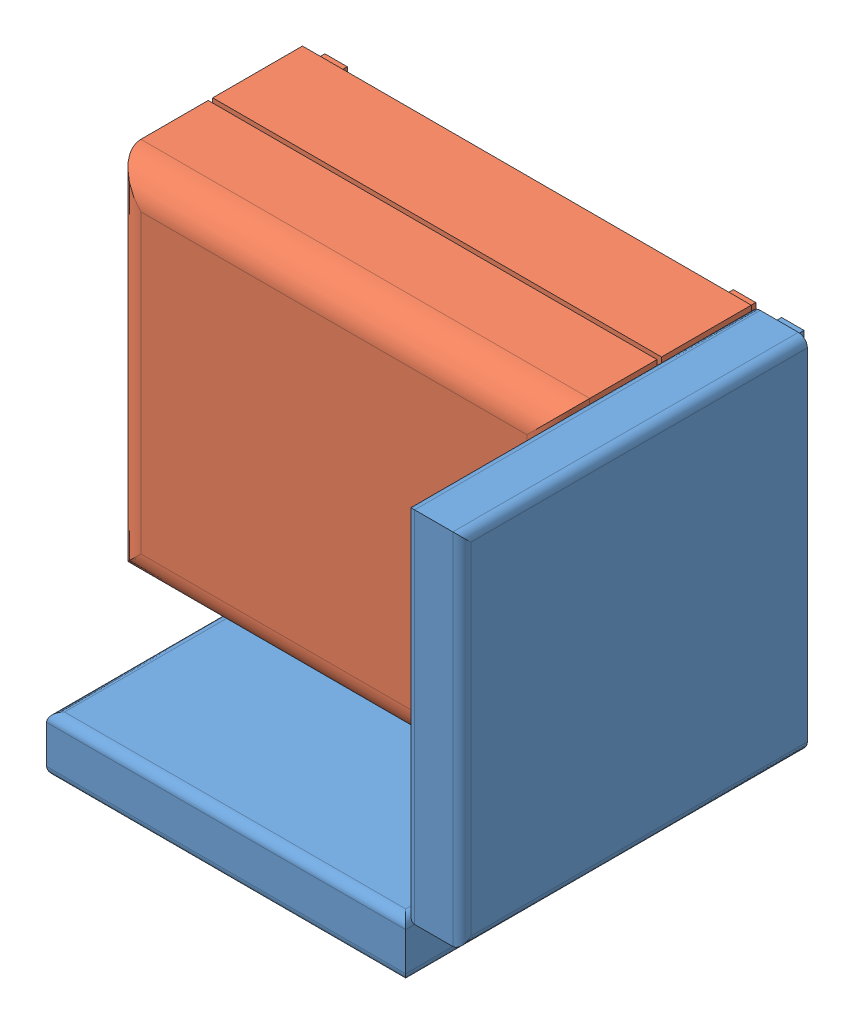
SolidWorks assembly Sofa-L, configuration Standard. Lengths in mm.
Overall size (1125 925 800).
3 component instances, 2 part files, 6 mates.
Components (placement in the parent):
- Rückenstütze-80x80-1: Rückenstütze-80x80 [Standard] at (24.1666 -782.5921 757.5769) size (800 125 800)
- Sitzelement-1: Sitzelement [Standard] at (-75.8334 -320.0921 787.5769) x (0 -1 0) z (-1 0 0) size (800 460 1000)
- Rückenstütze-80x80-3: Rückenstütze-80x80 [Standard] at (486.6666 -320.0921 757.5769) x (0 -1 0) z (0 0 1) size (800 125 800)
Mates (geometry in assembly coordinates):
- Deckungsgleich2: coincident aligned: plane of Rückenstütze-80x80-1 through (24.1666 -782.5921 757.5769) normal (0 0 -1); plane of Sitzelement-1 through (-75.8334 -320.0921 757.5769) normal (0 0 -1)
- Deckungsgleich3: coincident aligned: plane of Rückenstütze-80x80-1 through (424.1666 -845.0921 1557.5769) normal (1 0 0); plane of Sitzelement-1 through (424.1666 79.9079 987.5769) normal (1 0 0)
- Deckungsgleich13: coincident anti-aligned: plane of Rückenstütze-80x80-1 through (-375.8334 -720.0921 1557.5769) normal (0 1 0); plane of Sitzelement-1 through (-575.8334 -720.0921 987.5769) normal (0 -1 0)
- Deckungsgleich14: coincident: plane of Sitzelement-1 through (-75.8334 -320.0921 757.5769) normal (0 0 -1); plane of Rückenstütze-80x80-3 through (449.1666 -320.0921 757.5769) normal (0 0 -1)
- Deckungsgleich15: coincident anti-aligned: plane of Sitzelement-1 through (424.1666 79.9079 987.5769) normal (1 0 0); plane of Rückenstütze-80x80-3 through (424.1666 79.9079 1557.5769) normal (-1 0 0)
- Deckungsgleich16: coincident: plane of Sitzelement-1 through (-575.8334 -720.0921 987.5769) normal (0 -1 0); plane of Rückenstütze-80x80-3 through (386.6666 -720.0921 1557.5769) normal (0 -1 0)
